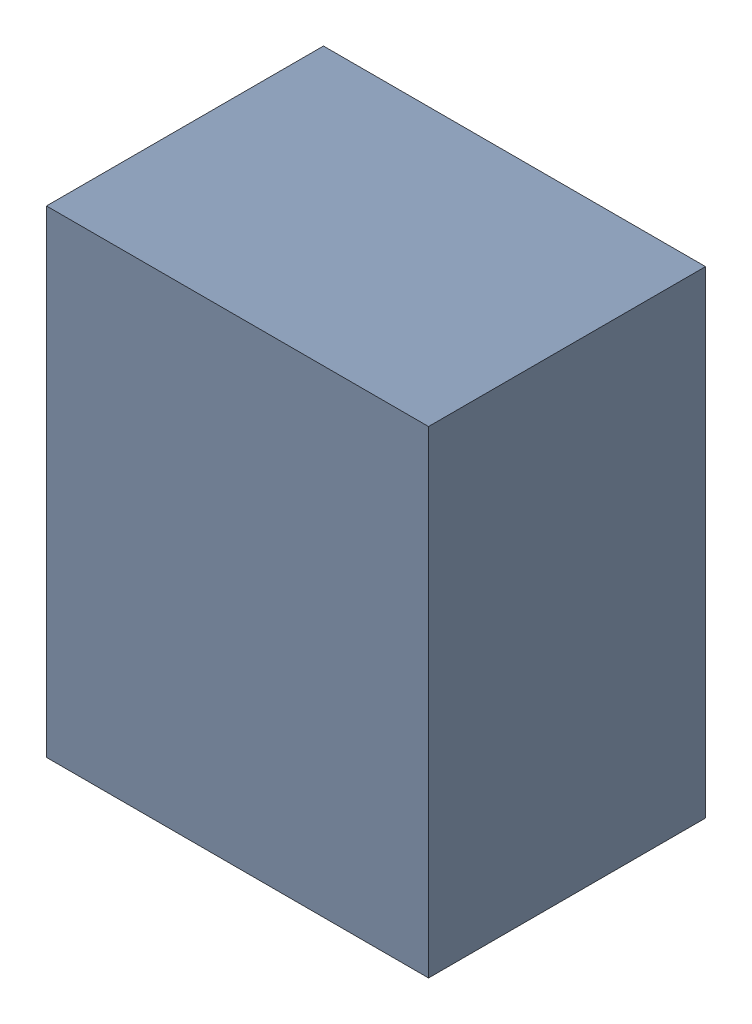
SolidWorks assembly U18, configuration Default. Lengths in mm.
Overall size (0.8 1 0.58).
2 component instances, 1 part files, 0 mates.
Components (placement in the parent):
- 836751984-1: 836751984 [Default] at (133.05 55.5 0.5) size (0.8 1 0.58)
  - Extruded_32-1: Extruded_32 [Default] at origin size (0.8 1 0.58)
